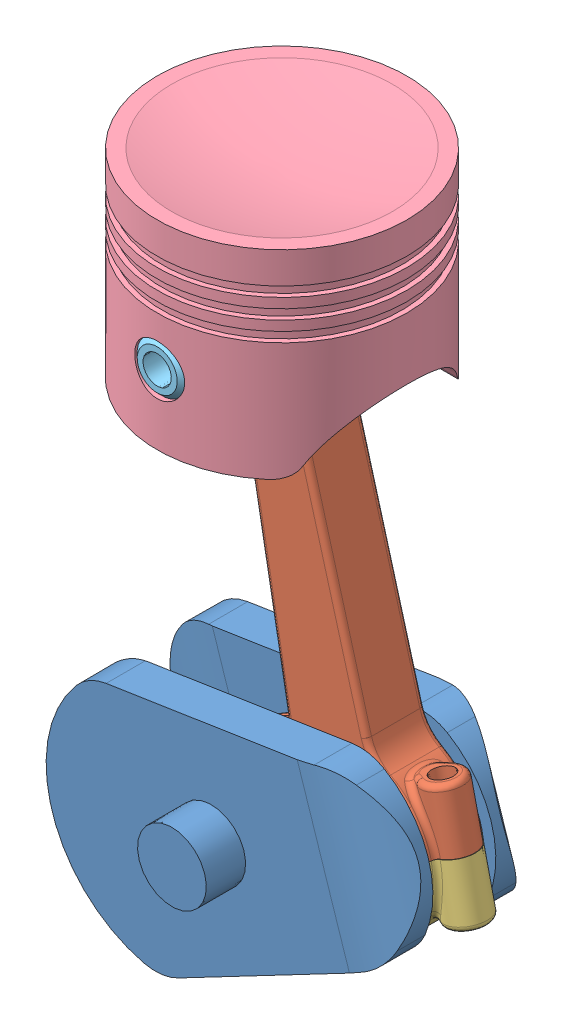
SolidWorks assembly ICEngine, configuration Default. Lengths in mm.
Overall size (207.87 371.38 127).
5 component instances, 5 part files, 12 mates.
Components (placement in the parent):
- Crank-1: Crank [Default] at (0 0 36) x (0.312715 -0.949847 0) z (0 0 1) size (118 180 112)
- Connecting_Rod-1: Connecting_Rod [Default] at (0 222.7606 72) x (0.223493 -0.974705 0) z (0 0 1) size (235.2 103.75 64.36)
- EndCap-1: EndCap [Default] at (47.4924 15.6357 72) x (0.223493 -0.974705 0) z (0 0 1) size (41.88 104.25 30.01)
- Piston-1: Piston [Default] at (0 262.7606 72) size (127 101.3 127)
- Wristpin-1: Wristpin [Default] at (0 222.7606 72) x (0.930647 0.365917 0) z (0 0 1) size (25.4 25.4 127)
Mates (geometry in assembly coordinates):
- Coincident1: coincident: line of Crank-1 through (0 0 128) axis (0 0 -1)
- Coincident2: coincident: line of Crank-1 through (0 0 128) axis (0 0 -1)
- Distance2: distance = 36 mm aligned: plane of Crank-1 through (0 0 36) normal (0 0 1)
- Coincident3: coincident anti-aligned: line of Connecting_Rod-1 through (48.1854 78.1852 72) axis (0.034205 -0.999415 0); line of EndCap-1 through (50.0513 23.6671 72) axis (-0.034205 0.999415 0)
- Coincident4: coincident anti-aligned: plane of Connecting_Rod-1; plane of EndCap-1
- Coincident6: coincident aligned: line of Crank-1 through (7.2687 49.4688 88) axis (0 0 -1); line of EndCap-1 through (7.2687 49.4688 87) axis (0 0 -1)
- Distance3: distance = 1 mm anti-aligned: plane of Connecting_Rod-1 through (47.4924 15.6357 87) normal (0 0 1); plane of Crank-1 through (42.7431 14.0722 88) normal (0 0 -1)
- Coincident8: coincident anti-aligned: line of Piston-1 through (0 261.8445 8.5) axis (0 0 1); line of Wristpin-1 through (0 261.8445 133) axis (0 0 -1)
- Coincident9: coincident aligned: plane of Piston-1 through (0 301.8445 72) normal (0 0 1); plane of Wristpin-1 through (0 261.8445 72) normal (0 0 1)
- Coincident10: coincident aligned: line of Connecting_Rod-1 through (0 261.8445 84.3) axis (0 0 -1); line of Wristpin-1 through (0 261.8445 133) axis (0 0 -1)
- Coincident11: coincident aligned: plane of Connecting_Rod-1 through (0 261.8445 72) normal (0 0 1); plane of Piston-1 through (0 301.8445 72) normal (0 0 1)
- Coincident12: coincident aligned: plane of Piston-1 through (0 301.8445 72) normal (1 0 0)
